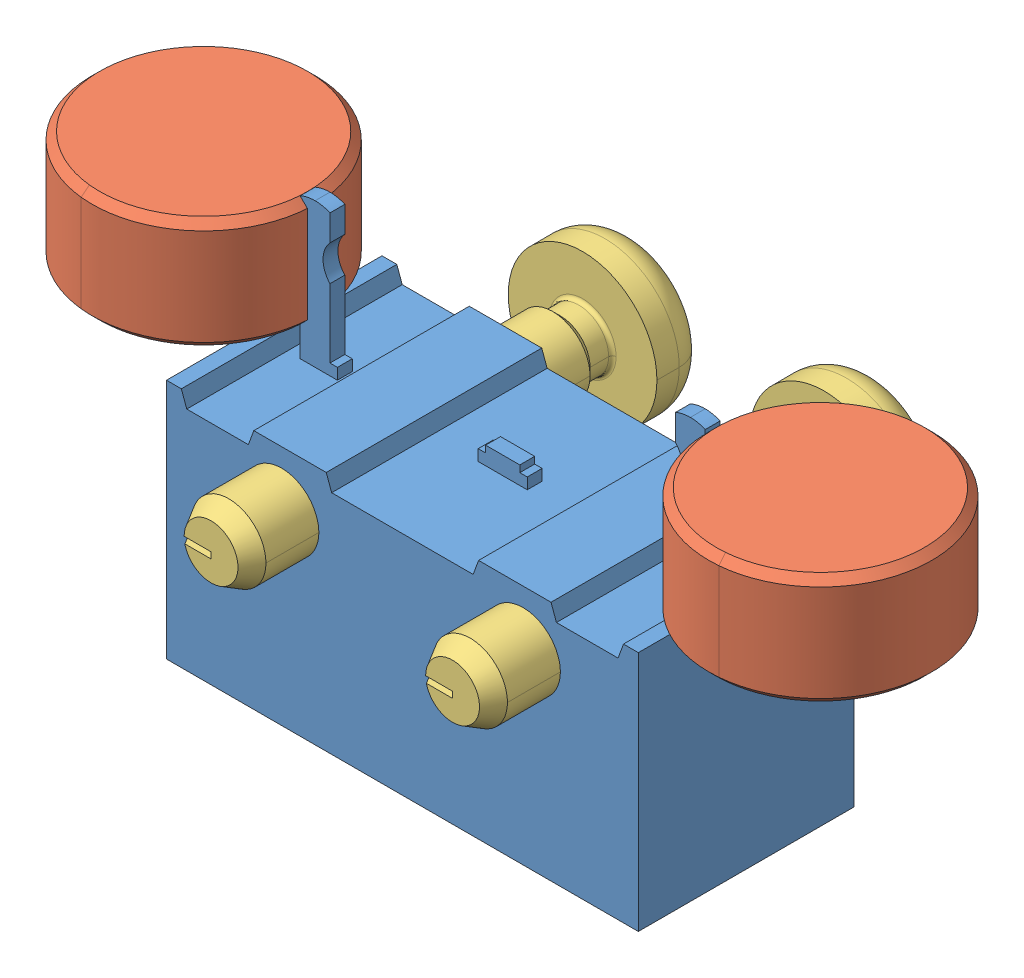
SolidWorks assembly Omron_Mag_Probe_Assembly.STEP, configuration Default. Lengths in mm.
Overall size (23.14 10.48 11.4).
6 component instances, 4 part files, 0 mates.
Components (placement in the parent):
- Probe_holder_d2f.STEP-1: Probe_holder_d2f.STEP [Default] at (5.956 9.8975 28.3867) size (26.49 8.9 10.41) (hidden)
- OMRON_D2F_Switch.STEP-1: OMRON_D2F_Switch.STEP [Default] at (12.356 12.5975 25.3867) x (0 0 1) z (0 -1 0) size (5.8 12.7 10.48)
- 6x3_Magnet.STEP-1: 6x3_Magnet.STEP [Default] at (4.106 16.3975 25.3867) x (0.994595 0 0.103833) z (-0.103833 0 0.994595) size (6 3 6)
- 6x3_Magnet.STEP-2: 6x3_Magnet.STEP [Default] at (20.706 16.3975 25.3867) x (0.996341 0 -0.085464) z (0.085464 0 0.996341) size (6 3 6)
- pan head tapping screw_am(PHT 2x10x9.2-type I-D-N).STEP-1: pan head tapping screw_am(PHT 2x10x9.2-type I-D-N).STEP [Default] at (15.606 14.4975 18.7867) x (0 0 1) z (-1 0 0) size (11.4 4 4)
- pan head tapping screw_am(PHT 2x10x9.2-type I-D-N).STEP-2: pan head tapping screw_am(PHT 2x10x9.2-type I-D-N).STEP [Default] at (9.106 14.4975 18.7867) x (0 0 1) z (-1 0 0) size (11.4 4 4)
